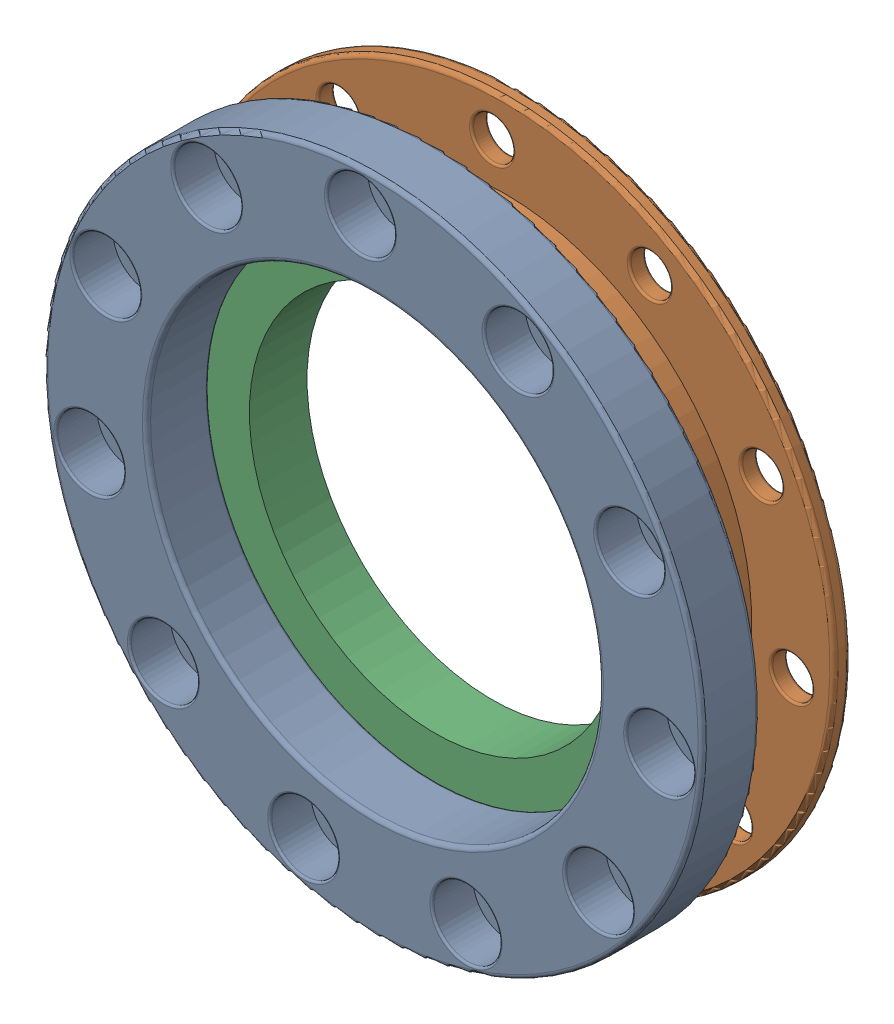
SolidWorks assembly RR_20238_50External Upper Bearing Housing_V2_27_29_10 pm_31_12pm_9pm, configuration Default. Lengths in mm.
Overall size (101.55 101.55 18).
3 component instances, 3 part files, 4 mates.
Components (placement in the parent):
- RR_20238_50outer bearing housing outer part PET Quantity 4_V2_27_29_10 pm_31_12pm_9pm-1: RR_20238_50outer bearing housing outer part PET Quantity 4_V2_27_29_10 pm_31_12pm_9pm [Default] at (9.3093 29.8688 63.0955) x (0.946419 0.322942 0) z (0 0 -1) size (80 80 11)
- RR_20238_50outer bearing housing_V2_27_29_10 pm_31_12pm_9pm-1: RR_20238_50outer bearing housing_V2_27_29_10 pm_31_12pm_9pm [Default] at (9.3093 29.8688 42.0955) x (0.999065 0.043224 0) z (0 0 1) size (80 80 7)
- RR_20238_5045-58-7_V2_27_29_10 pm_31_12pm_9pm-1: RR_20238_5045-58-7_V2_27_29_10 pm_31_12pm_9pm [Default] at (9.3093 29.8688 45.5955) size (58 58 7)
Mates (geometry in assembly coordinates):
- Coincident2: coincident anti-aligned: plane of outer bearing housing outer part-1 through (9.3093 29.8688 49.0955) normal (0 0 -1); plane of outer bearing housing-1 through (9.3093 29.8688 49.0955) normal (0 0 1)
- Concentric3: concentric aligned: cylinder of outer bearing housing outer part-1 through (40.4882 45.7709 49.0955) axis (0 0 1) radius 2.5; cylinder of outer bearing housing-1 through (40.4882 45.7709 42.0955) axis (0 0 1) radius 2.5
- Concentric4: concentric anti-aligned: cylinder of outer bearing housing outer part-1 through (9.3093 29.8688 53.0955) axis (0 0 1) radius 29; cylinder of 45-58-7-1 through (9.3093 29.8688 52.5955) axis (0 0 -1) radius 29
- Coincident3: coincident anti-aligned: plane of outer bearing housing-1 through (9.3093 29.8688 45.5955) normal (0 0 1); plane of 45-58-7-1 through (9.3093 29.8688 45.5955) normal (0 0 -1)
